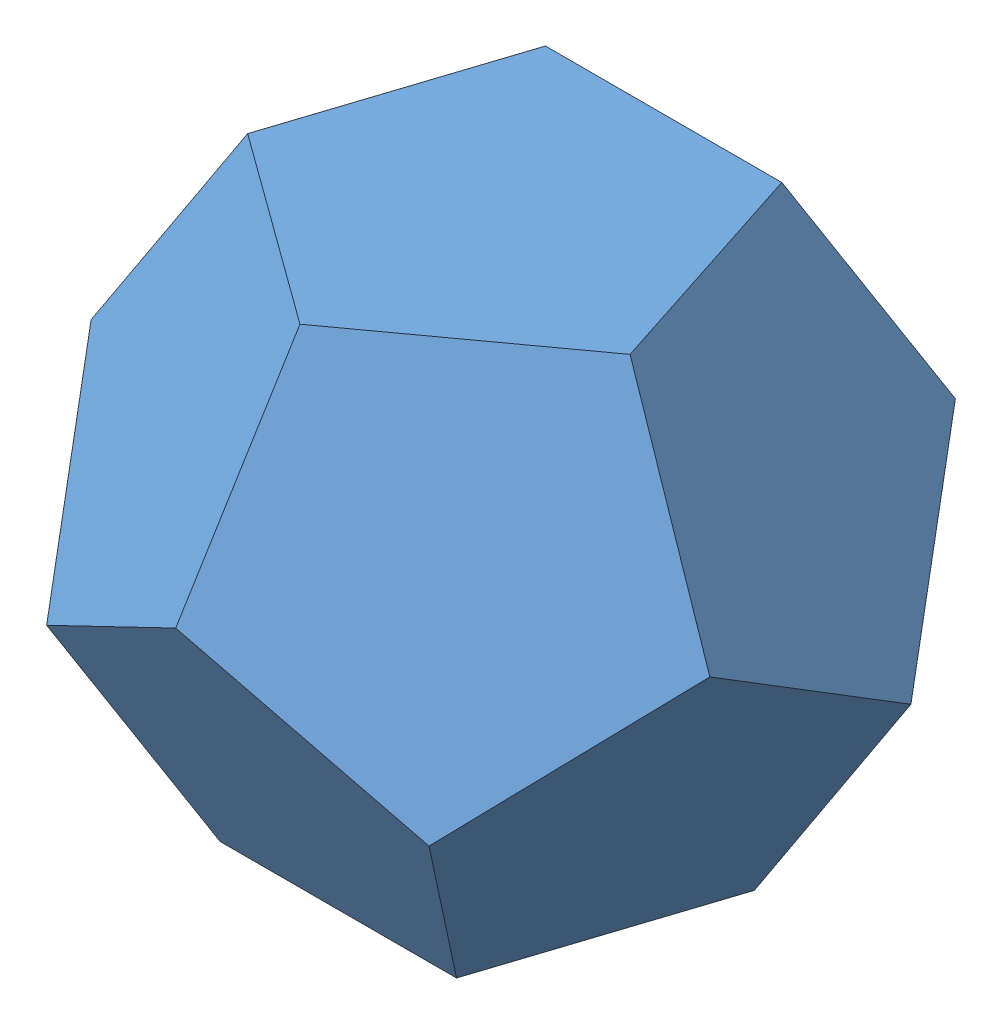
SolidWorks assembly Assem3, configuration Default. Lengths in mm.
Overall size (52.38 45.76 46.16).
4 component instances, 1 part files, 8 mates.
Components (placement in the parent):
- 3 Pyramid-1: 3 Pyramid [Default] at origin size (26.9 17.48 28.28)
- 3 Pyramid-2: 3 Pyramid [Default] at (7.4347 20.466 10.233) x (0.809017 0 -0.587785) z (-0.262866 0.894427 -0.361803) size (26.9 17.48 28.28)
- 3 Pyramid-3: 3 Pyramid [Default] at (-7.4347 7.8173 -10.233) x (-0.5 -0.525731 0.688191) z (-0.688191 0.723607 0.052786) size (26.9 17.48 28.28)
- 3 Pyramid-4: 3 Pyramid [Default] at (7.4347 7.8173 -10.233) x (-0.5 0.525731 -0.688191) z (0.688191 0.723607 0.052786) size (26.9 17.48 28.28)
Mates (geometry in assembly coordinates):
- Coincident9: coincident anti-aligned: plane of 3 Pyramid-1 through (0 17.4801 17.4801) normal (-0.5 0.850651 -0.16246); plane of 3 Pyramid-2 through (-10.2745 10.8033 14.1417) normal (0.5 -0.850651 0.16246)
- Coincident10: coincident aligned: line of 3 Pyramid-1 through (0 14.1417 0) axis (0 0.187592 0.982247); line of 3 Pyramid-2 through (0 14.1417 0) axis (0 0.187592 0.982247)
- Coincident17: coincident aligned: line of 3 Pyramid-1 through (0 14.1417 0) axis (0.57735 -0.794654 -0.187592); line of 3 Pyramid-4 through (0 14.1417 0) axis (0.57735 -0.794654 -0.187592)
- Coincident18: coincident anti-aligned: plane of 3 Pyramid-1 through (10.2745 0 -3.3384) normal (0.5 0.525731 -0.688191); plane of 3 Pyramid-4 through (0 0 -10.8033) normal (-0.5 -0.525731 0.688191)
- Coincident19: coincident aligned: line of 3 Pyramid-1 through (0 14.1417 0) axis (-0.934172 -0.187592 -0.303531); line of 3 Pyramid-3 through (0 14.1417 0) axis (-0.934172 -0.187592 -0.303531)
- Coincident20: coincident anti-aligned: plane of 3 Pyramid-1 through (-16.6245 10.8033 -5.4016) normal (0.309017 0 -0.951057); plane of 3 Pyramid-3 through (-16.6245 10.8033 -5.4016) normal (-0.309017 0 0.951057)
- Coincident21: coincident: point of 3 Pyramid-2; point of 3 Pyramid-4
- Coincident22: coincident: point of 3 Pyramid-3; point of 3 Pyramid-4
